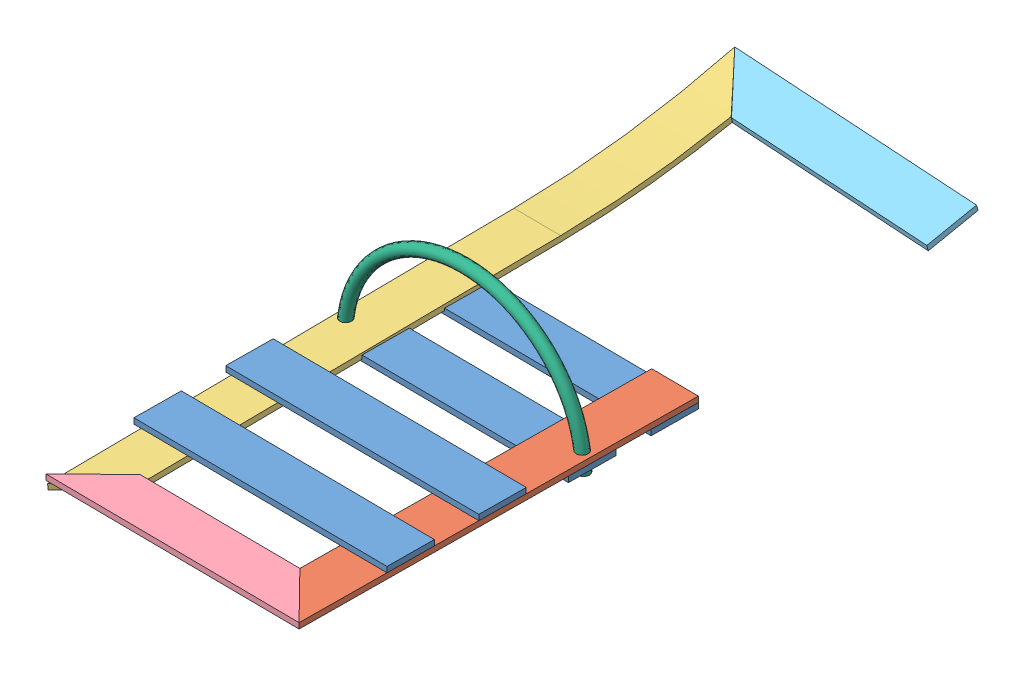
SolidWorks assembly Assem1, configuration Default. Lengths in mm.
Overall size (141.08 67.67 371.05).
9 component instances, 6 part files, 22 mates.
Components (placement in the parent):
- 3mm Flat plate-1: 3mm Flat plate [Default] at (-91.1769 68.6461 146.4058) x (0.999962 0 0.008727) z (-0.008727 0 0.999962) size (138 3 25.4)
- 3mm Flat plate-2: 3mm Flat plate [Default] at (-91.5619 74.6461 194.4198) x (0.999962 0 0.008727) z (-0.008727 0 0.999962) size (138 3 25.4)
- 3mm Flat plate-3: 3mm Flat plate [Default] at (-91.9915 74.6461 243.6461) x (0.999962 0 0.008727) z (-0.008727 0 0.999962) size (138 3 25.4)
- 3mm x 214mm flat plate-1: 3mm x 214mm flat plate [Default] at (-43.6199 71.6461 183.3655) x (-0.008727 0 0.999962) z (-0.999962 0 -0.008727) size (214 3 25.4)
- 3mm x 360mm flat plat-1: 3mm x 360mm flat plat [Default] at (-124.2658 71.6461 67.5773) x (-0.008727 0 0.999962) z (-0.999962 0 -0.008727) size (368.98 24.92 25.4)
- 3mm x 138mm x corner cut-1: 3mm x 138mm x corner cut [Default] at (-54.9282 71.6461 266.9585) x (0.999962 0 0.008727) z (-0.008727 0 0.999962) size (138 3 25.4)
- 3mm Flat plate-4: 3mm Flat plate [Default] at (-90.7566 68.6461 102.1434) x (0.999962 0 0.008727) z (-0.008727 0 0.999962) size (138 3 25.4)
- 3mm x 138mm single corner cut-1: 3mm x 138mm single corner cut [Default] at (-47.0897 79.3421 -37.2806) x (0.998608 -0.011474 0.051476) z (-0.052691 -0.258905 0.964465) size (138 3 26.42)
- foot holder-1: foot holder [Default] at (-142.0628 65.0037 140.666) size (135.35 67.67 6.35)
Mates (geometry in assembly coordinates):
- Coincident1: coincident: plane of 3mm x 360mm flat plat-1 through (-147.6474 59.7582 295.5089) normal (0.70091 -0.014107 0.71311); plane of 3mm x 138mm x corner cut-1 through (-147.6934 74.6461 296.589) normal (-0.700909 0 -0.71325)
- Coincident2: coincident: plane of 3mm x 360mm flat plat-1 through (-124.2588 74.3281 66.7787) normal (-0.000174 0.999801 0.019949); plane of 3mm x 138mm x corner cut-1 through (-54.9282 74.6461 266.9585) normal (0 1 0)
- Lock1: lock: unknown of 3mm x 360mm flat plat-1; unknown of 3mm x 138mm x corner cut-1
- Coincident3: coincident: plane of 3mm x 214mm flat plate-1 through (-9.6961 64.6461 297.7958) normal (-0.71325 0 0.700909); plane of 3mm x 138mm x corner cut-1 through (-9.6987 74.6461 297.7932) normal (0.71325 0 -0.700909)
- Coincident4: coincident: plane of 3mm x 214mm flat plate-1 through (-43.6199 74.6461 183.3655) normal (0 1 0); plane of 3mm x 138mm x corner cut-1 through (-54.9282 74.6461 266.9585) normal (0 1 0)
- Lock2: lock: unknown of 3mm x 214mm flat plate-1; unknown of 3mm x 138mm x corner cut-1
- Coincident7: coincident: plane of 3mm Flat plate-2 through (-91.5619 74.6461 194.4198) normal (0 -1 0); plane of 3mm x 360mm flat plat-1 through (-124.2588 74.3281 66.7787) normal (-0.000174 0.999801 0.019949)
- Coincident8: coincident aligned: plane of 3mm Flat plate-2 through (-146.5946 77.6461 174.8765) normal (-0.999962 0 -0.008727); plane of 3mm x 360mm flat plat-1 through (-144.5082 76.9381 -64.2063) normal (-0.999962 0 -0.008727)
- Coincident9: coincident: plane of 3mm Flat plate-3 through (-91.9915 74.6461 243.6461) normal (0 -1 0); plane of 3mm x 360mm flat plat-1 through (-124.2588 74.3281 66.7787) normal (-0.000174 0.999801 0.019949)
- Coincident10: coincident aligned: plane of 3mm Flat plate-3 through (-147.0242 77.6461 224.1027) normal (-0.999962 0 -0.008727); plane of 3mm x 360mm flat plat-1 through (-144.5082 76.9381 -64.2063) normal (-0.999962 0 -0.008727)
- Coincident11: coincident: plane of 3mm x 360mm flat plat-1 through (-124.2583 71.3287 66.7188) normal (0.000174 -0.999801 -0.019949); plane of 3mm Flat plate-4 through (-90.7566 71.6461 102.1434) normal (0 1 0)
- Coincident12: coincident: plane of 3mm x 360mm flat plat-1 through (-144.5082 76.9381 -64.2063) normal (-0.999962 0 -0.008727); plane of 3mm Flat plate-4 through (-145.7894 71.6461 82.6) normal (-0.999962 0 -0.008727)
- Coincident13: coincident: plane of 3mm x 214mm flat plate-1 through (-7.8287 74.6461 83.804) normal (0.008727 0 -0.999962); plane of 3mm Flat plate-4 through (-145.7894 71.6461 82.6) normal (0.008727 0 -0.999962)
- Lock4: lock: unknown of 3mm Flat plate-2; unknown of 3mm x 360mm flat plat-1
- Lock5: lock: unknown of 3mm x 360mm flat plat-1; unknown of 3mm Flat plate-4
- Lock6: lock: unknown of 3mm Flat plate-3; unknown of 3mm x 360mm flat plat-1
- Coincident18: coincident: plane of 3mm Flat plate-1 through (-91.1769 71.6461 146.4058) normal (0 1 0); plane of 3mm x 214mm flat plate-1 through (-43.6199 71.6461 183.3655) normal (0 -1 0)
- Coincident19: coincident: plane of 3mm Flat plate-1 through (-8.2149 71.6461 128.0667) normal (0.999962 0 0.008727); plane of 3mm x 214mm flat plate-1 through (-7.8287 74.6461 83.804) normal (0.999962 0 0.008727)
- Lock8: lock: unknown of 3mm x 214mm flat plate-1; unknown of foot holder-1
- Tangent1: tangent: face of 3mm x 360mm flat plat-1; plane of 3mm x 138mm single corner cut-1 through (-144.428 91.6602 -72.4625) normal (-0.743961 -0.174794 0.644956)
- Tangent2: tangent: cylinder of 3mm x 360mm flat plat-1 through (-145.5532 564.6859 55.5434) axis (0.999962 0 0.008727) radius 490.0398; plane of 3mm x 138mm single corner cut-1 through (-47.0965 82.2396 -36.5031) normal (-0.002262 0.965835 0.259149)
- Lock9: lock: unknown of 3mm x 360mm flat plat-1; unknown of 3mm x 138mm single corner cut-1
